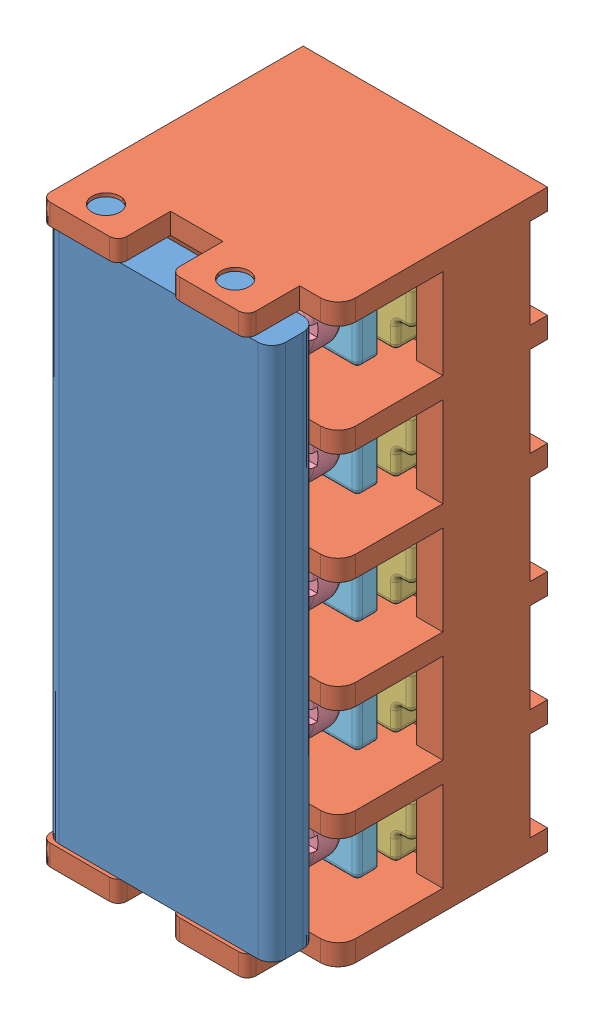
SolidWorks assembly Screw TerminalS-60-12, configuration Default. Lengths in mm.
Overall size (14 33 18).
22 component instances, 5 part files, 8 mates.
Components (placement in the parent):
- Cover_0^Screw TerminalS-60-12-1: Cover_0^Screw TerminalS-60-12 [Default] at (60.5 25.5 20.7) x (0 1 0) z (0 0 1) size (32.6 13 2.6) (virtual)
- Corpo^Screw TerminalS-60-12-1: Corpo^Screw TerminalS-60-12 [Default] at (79 25.5 8.5) x (0 1 0) z (0 0 1) size (33 14 15) (virtual)
- GruppoVite^Screw TerminalS-60-12-1: GruppoVite^Screw TerminalS-60-12 [Default] at origin size (7.91 5.27 13.79) (virtual)
  - DadoBasso^GruppoVite_Screw TerminalS-60-12-1: DadoBasso^GruppoVite_Screw TerminalS-60-12 [Default] at (79.8845 28.4079 8.4556) x (0 1 0) z (0 0 1) size (5.27 7.91 9.5) (virtual)
  - M3x06_MOD v4^GruppoVite_Screw TerminalS-60-12-1: M3x06_MOD v4^GruppoVite_Screw TerminalS-60-12 [Default] at (80.5 12.78 16.9) x (0 1 0) z (0 0 1) size (4.5 4.5 8.39) (virtual)
  - DadoAlto^GruppoVite_Screw TerminalS-60-12-1: DadoAlto^GruppoVite_Screw TerminalS-60-12 [Default] at (80.45 -12.22 15.7) x (0 1 0) z (0 0 1) size (4.8 6.11 1.26) (virtual)
- GruppoVite^Screw TerminalS-60-12-2: GruppoVite^Screw TerminalS-60-12 [Default] at (0 6.3694 0) size (7.91 5.27 13.79) (virtual)
  - DadoBasso^GruppoVite_Screw TerminalS-60-12-1: DadoBasso^GruppoVite_Screw TerminalS-60-12 [Default] at (79.8845 28.4079 8.4556) x (0 1 0) z (0 0 1) size (5.27 7.91 9.5) (virtual)
  - M3x06_MOD v4^GruppoVite_Screw TerminalS-60-12-1: M3x06_MOD v4^GruppoVite_Screw TerminalS-60-12 [Default] at (80.5 12.78 16.9) x (0 1 0) z (0 0 1) size (4.5 4.5 8.39) (virtual)
  - DadoAlto^GruppoVite_Screw TerminalS-60-12-1: DadoAlto^GruppoVite_Screw TerminalS-60-12 [Default] at (80.45 -12.22 15.7) x (0 1 0) z (0 0 1) size (4.8 6.11 1.26) (virtual)
- GruppoVite^Screw TerminalS-60-12-3: GruppoVite^Screw TerminalS-60-12 [Default] at (0 12.7319 0) size (7.91 5.27 13.79) (virtual)
  - DadoBasso^GruppoVite_Screw TerminalS-60-12-1: DadoBasso^GruppoVite_Screw TerminalS-60-12 [Default] at (79.8845 28.4079 8.4556) x (0 1 0) z (0 0 1) size (5.27 7.91 9.5) (virtual)
  - M3x06_MOD v4^GruppoVite_Screw TerminalS-60-12-1: M3x06_MOD v4^GruppoVite_Screw TerminalS-60-12 [Default] at (80.5 12.78 16.9) x (0 1 0) z (0 0 1) size (4.5 4.5 8.39) (virtual)
  - DadoAlto^GruppoVite_Screw TerminalS-60-12-1: DadoAlto^GruppoVite_Screw TerminalS-60-12 [Default] at (80.45 -12.22 15.7) x (0 1 0) z (0 0 1) size (4.8 6.11 1.26) (virtual)
- GruppoVite^Screw TerminalS-60-12-4: GruppoVite^Screw TerminalS-60-12 [Default] at (0 19.0736 0) size (7.91 5.27 13.79) (virtual)
  - DadoBasso^GruppoVite_Screw TerminalS-60-12-1: DadoBasso^GruppoVite_Screw TerminalS-60-12 [Default] at (79.8845 28.4079 8.4556) x (0 1 0) z (0 0 1) size (5.27 7.91 9.5) (virtual)
  - M3x06_MOD v4^GruppoVite_Screw TerminalS-60-12-1: M3x06_MOD v4^GruppoVite_Screw TerminalS-60-12 [Default] at (80.5 12.78 16.9) x (0 1 0) z (0 0 1) size (4.5 4.5 8.39) (virtual)
  - DadoAlto^GruppoVite_Screw TerminalS-60-12-1: DadoAlto^GruppoVite_Screw TerminalS-60-12 [Default] at (80.45 -12.22 15.7) x (0 1 0) z (0 0 1) size (4.8 6.11 1.26) (virtual)
- GruppoVite^Screw TerminalS-60-12-5: GruppoVite^Screw TerminalS-60-12 [Default] at (0 25.4377 0) size (7.91 5.27 13.79) (virtual)
  - DadoBasso^GruppoVite_Screw TerminalS-60-12-1: DadoBasso^GruppoVite_Screw TerminalS-60-12 [Default] at (79.8845 28.4079 8.4556) x (0 1 0) z (0 0 1) size (5.27 7.91 9.5) (virtual)
  - M3x06_MOD v4^GruppoVite_Screw TerminalS-60-12-1: M3x06_MOD v4^GruppoVite_Screw TerminalS-60-12 [Default] at (80.5 12.78 16.9) x (0 1 0) z (0 0 1) size (4.5 4.5 8.39) (virtual)
  - DadoAlto^GruppoVite_Screw TerminalS-60-12-1: DadoAlto^GruppoVite_Screw TerminalS-60-12 [Default] at (80.45 -12.22 15.7) x (0 1 0) z (0 0 1) size (4.8 6.11 1.26) (virtual)
Mates (geometry in assembly coordinates):
- Coincident1: coincident aligned: plane of Copy of GruppoVite^Screw TerminalS-60-12-1/DadoBasso-1 through (77.3 13.18 13.5) normal (1 0 0); plane of GruppoVite-2/DadoBasso-1 through (77.3 19.5494 13.5) normal (1 0 0)
- Coincident2: coincident aligned: plane of Copy of GruppoVite^Screw TerminalS-60-12-2/DadoBasso-1 through (77.3 19.5494 13.5) normal (1 0 0); plane of GruppoVite-3/DadoBasso-1 through (77.3 25.9119 13.5) normal (1 0 0)
- Coincident3: coincident aligned: plane of Copy of GruppoVite^Screw TerminalS-60-12-1/DadoBasso-1 through (77.3 13.18 13.5) normal (1 0 0); plane of GruppoVite-4/DadoBasso-1 through (77.3 32.2536 13.5) normal (1 0 0)
- Coincident4: coincident aligned: plane of Copy of GruppoVite^Screw TerminalS-60-12-1/DadoBasso-1 through (77.3 13.18 13.5) normal (1 0 0); plane of GruppoVite-5/DadoBasso-1 through (77.3 38.6177 13.5) normal (1 0 0)
- Coincident5: coincident aligned: plane of Copy of GruppoVite^Screw TerminalS-60-12-1/DadoBasso-1 through (77.3 13.18 5.5) normal (0 0 -1); plane of GruppoVite-2/DadoBasso-1 through (77.3 19.5494 5.5) normal (0 0 -1)
- Coincident6: coincident aligned: plane of Copy of GruppoVite^Screw TerminalS-60-12-1/DadoBasso-1 through (77.3 13.18 5.5) normal (0 0 -1); plane of GruppoVite-3/DadoBasso-1 through (77.3 25.9119 5.5) normal (0 0 -1)
- Coincident7: coincident aligned: plane of Copy of GruppoVite^Screw TerminalS-60-12-1/DadoBasso-1 through (77.3 13.18 5.5) normal (0 0 -1); plane of GruppoVite-4/DadoBasso-1 through (77.3 32.2536 5.5) normal (0 0 -1)
- Coincident8: coincident aligned: plane of Copy of GruppoVite^Screw TerminalS-60-12-1/DadoBasso-1 through (77.3 13.18 5.5) normal (0 0 -1); plane of GruppoVite-5/DadoBasso-1 through (77.3 38.6177 5.5) normal (0 0 -1)
